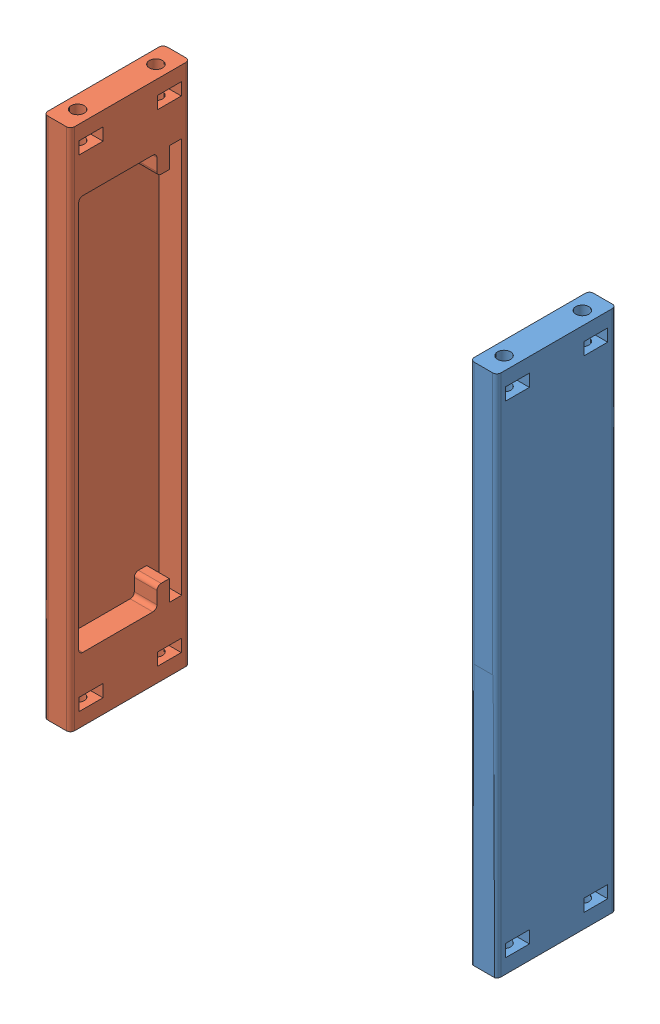
SolidWorks assembly Chassis, configuration Default. Lengths in mm.
Overall size (110 127 29).
2 component instances, 2 part files, 0 mates.
Components (placement in the parent):
- Chassis_Right_Side-1: Chassis_Right_Side [Default] at (205.6209 154.434 412.2666) x (0 0 1) z (-1 0 0) size (29 127 6.5)
- Chassis_Left_Side-1: Chassis_Left_Side [Default] at (95.6208 154.4341 412.2666) x (0 0 1) z (1 0 0) size (29 127 6.5)
